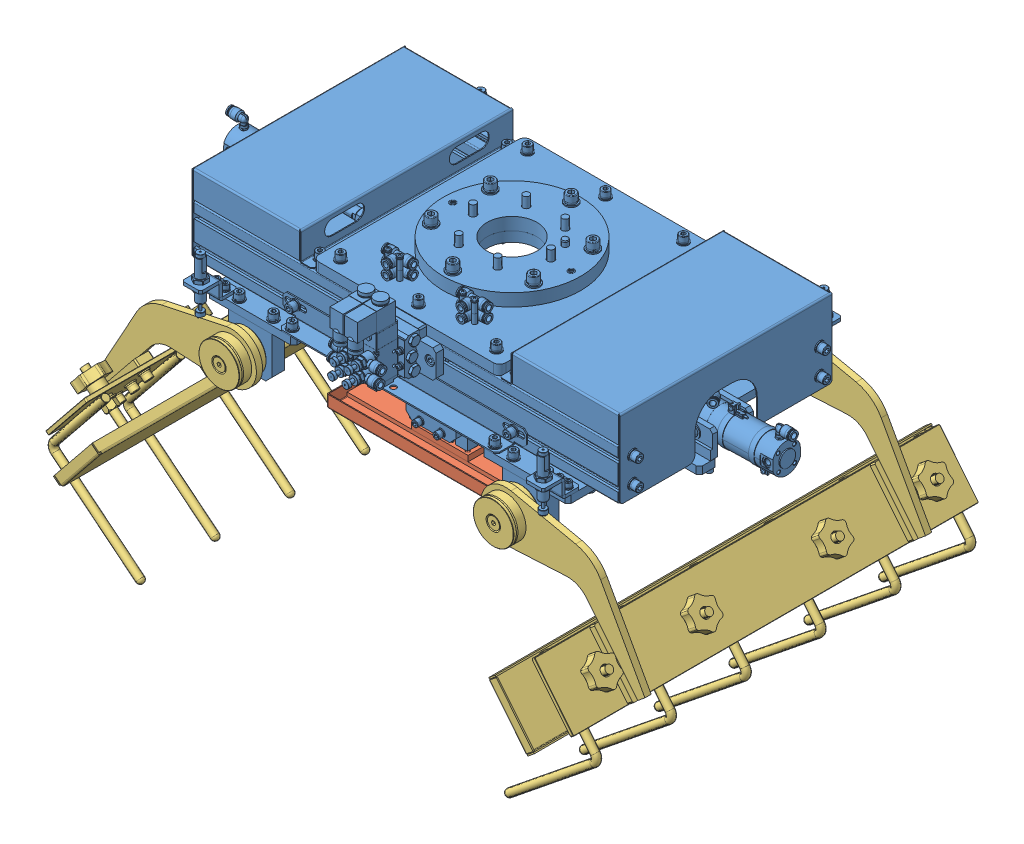
SolidWorks assembly CTABG430.00_码垛手-20220729-000, configuration 默认. Lengths in mm.
Overall size (905.57 514.96 700).
5 component instances, 3 part files, 15 mates.
Components (placement in the parent):
- CTABG430.00_码垛手-20220729-001-1: CTABG430.00_码垛手-20220729-001 [默认] at origin size (905.57 250.9 518.5)
- CTABG430.01_夹爪主体-20220728-001-1: CTABG430.01_夹爪主体-20220728-001 [默认] at origin size (300.29 103.15 100.29)
- CTABG430.01_夹爪主体-20220728-001-2: CTABG430.01_夹爪主体-20220728-001 [默认] at (0 0 -194) size (300.29 103.15 100.29)
- CTABG430.00_码垛手-20220729-002-1: CTABG430.00_码垛手-20220729-002 [默认] at (0.0025 0.0043 0) x (1 -0.00002 0) z (0 0 1) size (263.22 357.05 700)
- CTABG430.00_码垛手-20220729-002-2: CTABG430.00_码垛手-20220729-002 [默认] at (-0.0025 0.0043 0) x (-1 -0.00002 0) z (0 0 -1) size (263.22 357.05 700)
Mates (geometry in assembly coordinates):
- 重合1: coincident aligned: plane of CTABG430.00_码垛手-20220729-001-1 through (0 0 0) normal (0 0 1); plane of assembly through (0 0 0) normal (0 0 1)
- 重合2: coincident aligned: plane of CTABG430.00_码垛手-20220729-001-1 through (0 0 0) normal (0 1 0); plane of assembly through (0 0 0) normal (0 1 0)
- 重合3: coincident aligned: plane of CTABG430.00_码垛手-20220729-001-1 through (0 0 0) normal (1 0 0); plane of assembly through (0 0 0) normal (1 0 0)
- 同心1: concentric aligned: cylinder of CTABG430.00_码垛手-20220729-001-1 through (-32 -92.5 97) axis (0 -1 0) radius 8; cylinder of CTABG430.01_夹爪主体-20220728-001-1 through (-32 -92.5 97) axis (0 -1 0) radius 8
- 同心2: concentric aligned: cylinder of CTABG430.00_码垛手-20220729-001-1 through (32 -92.5 97) axis (0 -1 0) radius 8; cylinder of CTABG430.01_夹爪主体-20220728-001-1 through (32 -92.5 97) axis (0 -1 0) radius 8
- LimitDistance1: limit distance = 7 mm anti-aligned: plane of CTABG430.01_夹爪主体-20220728-001-1 through (0 -187 97) normal (0 1 0); plane of CTABG430.00_码垛手-20220729-001-1 through (-5.5 -180 80.5) normal (0 -1 0)
- 同心3: concentric aligned: cylinder of CTABG430.00_码垛手-20220729-001-1 through (32 -92.5 -97) axis (0 -1 0) radius 8; cylinder of CTABG430.01_夹爪主体-20220728-001-2 through (32 -92.5 -97) axis (0 -1 0) radius 8
- 同心4: concentric aligned: cylinder of CTABG430.00_码垛手-20220729-001-1 through (-32 -92.5 -97) axis (0 -1 0) radius 8; cylinder of CTABG430.01_夹爪主体-20220728-001-2 through (-32 -92.5 -97) axis (0 -1 0) radius 8
- 重合6: coincident aligned: plane of CTABG430.01_夹爪主体-20220728-001-1 through (0 -203.5 97) normal (0 -1 0); plane of CTABG430.01_夹爪主体-20220728-001-2 through (0 -203.5 -97) normal (0 -1 0)
- 同心5: concentric aligned: cylinder of CTABG430.00_码垛手-20220729-001-1 through (220 -127 -180) axis (0 0 -1) radius 12.5; cylinder of CTABG430.00_码垛手-20220729-002-1 through (220 -127 -205) axis (0 0 -1) radius 32.5
- 重合7: coincident aligned: plane of CTABG430.00_码垛手-20220729-002-1 through (0.0025 0.0043 0) normal (0 0 1); plane of assembly through (0 0 0) normal (0 0 1)
- LimitAngle1: limit planar angle = 0.679457 rad anti-aligned: plane of CTABG430.00_码垛手-20220729-002-1 through (387.6815 -248.6508 0) normal (-0.777914 -0.62837 0); plane of assembly through (0 0 0) normal (1 0 0)
- 同心6: concentric anti-aligned: cylinder of CTABG430.00_码垛手-20220729-001-1 through (-220 -127 -180) axis (0 0 -1) radius 12.5; cylinder of CTABG430.00_码垛手-20220729-002-2 through (-220 -127 205) axis (0 0 1) radius 32.5
- 重合8: coincident aligned: plane of CTABG430.00_码垛手-20220729-002-1 through (220 -127 -250) normal (0 0 -1); plane of CTABG430.00_码垛手-20220729-002-2 through (-220 -127 -250) normal (0 0 -1)
- 对称1: symmetric aligned: plane of CTABG430.00_码垛手-20220729-002-1; plane of CTABG430.00_码垛手-20220729-002-2; plane of assembly through (0 0 0) normal (1 0 0)
